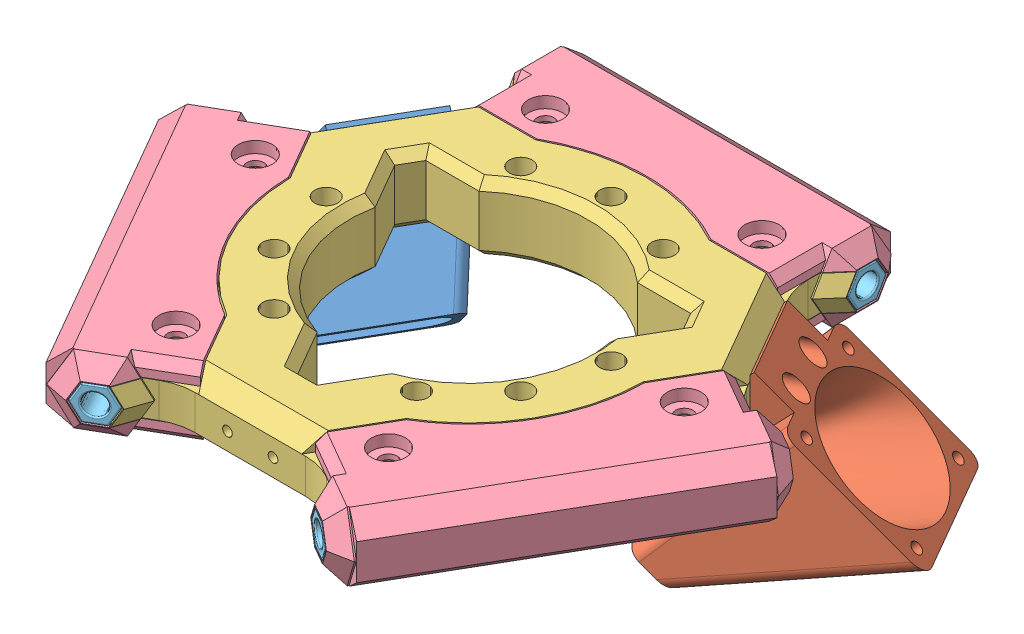
SolidWorks assembly end-effector-assembly, configuration Default. Lengths in mm.
Overall size (127.04 42.87 96.59).
9 component instances, 5 part files, 27 mates.
Components (placement in the parent):
- extrudate-fan-left-1: extrudate-fan-left [Default] at (-46.0569 -10 -26.591) x (-0.5 0 0.866025) z (0.612372 0.707107 0.353553) size (32 25.01 33.29)
- extrudate-fan-right-1: extrudate-fan-right [Default] at (46.0569 -10 -26.591) x (-0.5 0 -0.866025) z (-0.612372 0.707107 0.353553) size (32 25.01 33.29)
- end-effector-1: end-effector [Default] at origin size (96.08 12 83.21)
- end-effector-cover-1: end-effector-cover [Default] at origin size (60 14 19.82)
- end-effector-cover-2: end-effector-cover [Default] x (-0.5 0 -0.866025) z (0.866025 0 -0.5) size (60 14 19.82)
- end-effector-cover-3: end-effector-cover [Default] x (-0.5 0 0.866025) z (-0.866025 0 -0.5) size (60 14 19.82)
- standoff-60mm-1: standoff-60mm [Default] at (0 0 -40) x (0 -0.866025 -0.5) z (0 -0.5 0.866025) size (6.85 60 6)
- standoff-60mm-2: standoff-60mm [Default] at (34.641 0 20) x (0.433013 -0.866025 0.25) z (0.75 0.5 0.433013) size (6.85 60 6)
- standoff-60mm-3: standoff-60mm [Default] at (-34.641 0 20) x (0.433013 -0.866025 -0.25) z (-0.75 -0.5 0.433013) size (6.85 60 6)
Mates (geometry in assembly coordinates):
- Coincident12: coincident aligned: plane of end-effector-1 through (0 0 0) normal (0 0 1); plane of assembly through (0 0 0) normal (0 0 1)
- Coincident13: coincident aligned: plane of end-effector-1 through (0 0 0) normal (1 0 0); plane of assembly through (0 0 0) normal (1 0 0)
- Coincident14: coincident aligned: plane of end-effector-1 through (0 0 0) normal (0 1 0); plane of assembly through (0 0 0) normal (0 1 0)
- Coincident21: coincident aligned: plane of end-effector-cover-1 through (0 0 0) normal (0 1 0); plane of assembly through (0 0 0) normal (0 1 0)
- Coincident22: coincident aligned: plane of end-effector-cover-1 through (0 0 0) normal (0 0 1); plane of assembly through (0 0 0) normal (0 0 1)
- Coincident23: coincident aligned: plane of end-effector-cover-1 through (0 0 0) normal (1 0 0); plane of assembly through (0 0 0) normal (1 0 0)
- Coincident27: coincident aligned: plane of end-effector-cover-2; plane of assembly through (0 0 0) normal (0 1 0)
- Angle4: planar angle = 1.047198 rad anti-aligned: plane of end-effector-cover-2 through (0 0 0) normal (0.866025 0 -0.5); plane of assembly through (0 0 0) normal (0 0 1)
- Coincident29: coincident: axis of end-effector-1 through (0 4.5 0) axis (0 -1 0); point of end-effector-cover-2
- Angle5: planar angle = 2.094395 rad aligned: plane of end-effector-cover-3 through (0 0 0) normal (-0.866025 0 -0.5); plane of assembly through (0 0 0) normal (0 0 1)
- Coincident35: coincident aligned: plane of end-effector-cover-3; plane of assembly through (0 0 0) normal (0 1 0)
- Coincident39: coincident: axis of end-effector-1 through (0 4.5 0) axis (0 -1 0); point of end-effector-cover-3
- Concentric2: concentric anti-aligned: cylinder of extrudate-fan-left-1 through (-56.0219 0 -27.7255) axis (0.866025 0 0.5) radius 1; cylinder of end-effector-1 through (-28.7452 0 -11.9772) axis (-0.866025 0 -0.5) radius 0.85
- Concentric3: concentric anti-aligned: cylinder of extrudate-fan-left-1 through (-52.0219 0 -34.6537) axis (0.866025 0 0.5) radius 1; cylinder of end-effector-1 through (-24.7452 0 -18.9054) axis (-0.866025 0 -0.5) radius 0.85
- Coincident40: coincident anti-aligned: plane of extrudate-fan-left-1 through (-29.1971 4.8492 -26.0945) normal (0.866025 0 0.5); plane of end-effector-1 through (-22.1683 -3.05 -38.2688) normal (-0.866025 0 -0.5)
- Concentric4: concentric anti-aligned: cylinder of extrudate-fan-right-1 through (52.0219 0 -34.6537) axis (-0.866025 0 0.5) radius 1; cylinder of end-effector-1 through (24.7452 0 -18.9054) axis (0.866025 0 -0.5) radius 0.85
- Concentric5: concentric anti-aligned: cylinder of extrudate-fan-right-1 through (56.0219 0 -27.7255) axis (-0.866025 0 0.5) radius 1; cylinder of end-effector-1 through (28.7452 0 -11.9772) axis (0.866025 0 -0.5) radius 0.85
- Coincident41: coincident anti-aligned: plane of extrudate-fan-right-1 through (29.1971 4.8492 -26.0945) normal (-0.866025 0 0.5); plane of end-effector-1 through (44.2259 -3.05 -0.0639) normal (0.866025 0 -0.5)
- Coincident42: coincident aligned: plane of end-effector-1 through (30 0 0) normal (1 0 0); plane of standoff-60mm-1 through (30 0 -40) normal (1 0 0)
- Distance1: distance = 0.05 mm aligned: plane of standoff-60mm-1 through (30 3 -41.7321) normal (0 1 0); plane of end-effector-1 through (21.6313 3.05 -38.1525) normal (0 1 0)
- Distance2: distance = 40 mm: axis of standoff-60mm-1 through (29.75 0 -40) axis (-1 0 0); axis of end-effector-1 through (0 4.5 0) axis (0 -1 0)
- Coincident45: coincident aligned: plane of end-effector-1 through (15 0 -25.9808) normal (0.5 0 -0.866025); plane of standoff-60mm-2 through (49.641 0 -5.9808) normal (0.5 0 -0.866025)
- Distance3: distance = 0.05 mm aligned: plane of standoff-60mm-2 through (48.141 3 -6.8468) normal (0 1 0); plane of end-effector-1 through (43.8566 3.05 0.343) normal (0 1 0)
- Distance5: distance = 40 mm: axis of standoff-60mm-2 through (49.516 0 -5.7643) axis (-0.5 0 0.866025); axis of end-effector-1 through (0 4.5 0) axis (0 -1 0)
- Coincident49: coincident: plane of end-effector-1 through (15 0 25.9808) normal (0.5 0 0.866025); plane of standoff-60mm-3 through (-19.641 0 45.9808) normal (0.5 0 0.866025)
- Distance6: distance = 0.05 mm: plane of end-effector-1 through (-22.2254 3.05 37.8095) normal (0 1 0); plane of standoff-60mm-3 through (-18.141 3 45.1147) normal (0 1 0)
- Distance7: distance = 40 mm: axis of standoff-60mm-3 through (-19.766 0 45.7643) axis (-0.5 0 -0.866025); axis of end-effector-1 through (0 4.5 0) axis (0 -1 0)
